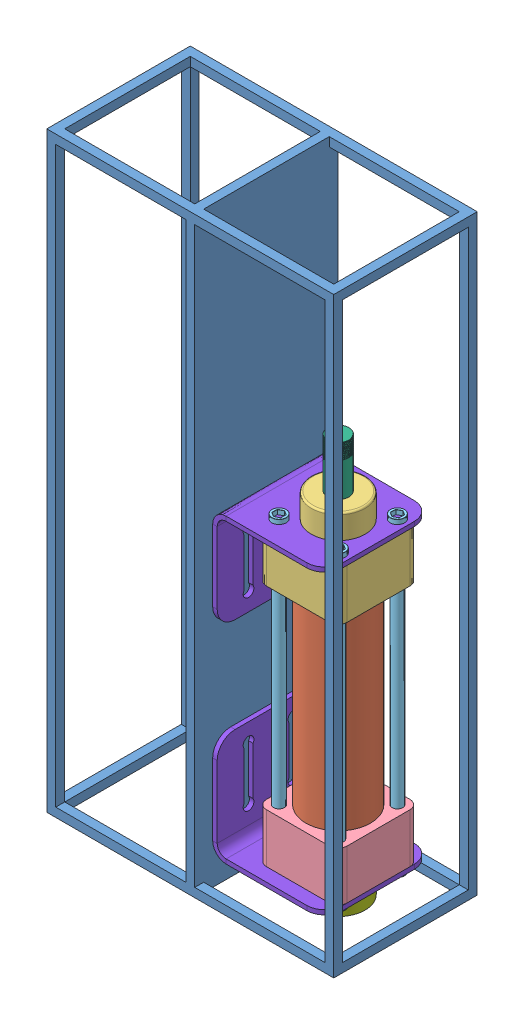
SolidWorks assembly Vertical Cylinder, configuration Default. Lengths in mm.
Overall size (160 330 80).
13 component instances, 8 part files, 3 mates.
Components (placement in the parent):
- Vertical Support-1: Vertical Support [Default] at (89.3378 424.6632 360.7176) x (1 0 0) z (0 -1 0) size (160 80 330)
- pnumetic cylinder-1: pnumetic cylinder [Default] at (92.3698 80.2595 293.179) x (-0.035384 0 0.999374) z (0 1 0) size (62.17 64.58 222.63) (flexible)
  - cylinder tube-1: cylinder tube [Default] at (103.244 123.1984 58.4037) size (36 36 110)
  - cylinder part one-1: cylinder part one [Default] at (126.5261 101.5086 194.9037) x (0.035384 -0.999374 0) z (0 0 -1) size (45 45 43.5)
  - cylinder part two1-1: cylinder part two1 [Default] at (124.9338 146.4804 31.9037) x (-0.035384 0.999374 0) z (0 0 1) size (45 45 27.5)
  - cylinder bolt-1: cylinder bolt [Default] at (87.3382 106.1249 113.4037) x (1 0 0) z (0 1 0) size (8 173 8)
  - cylinder bolt-2: cylinder bolt [Default] at (120.3176 107.2925 113.4037) x (1 0 0) z (0 1 0) size (8 173 8)
  - cylinder bolt-3: cylinder bolt [Default] at (119.1499 140.2719 113.4037) x (1 0 0) z (0 1 0) size (8 173 8)
  - cylinder bolt-4: cylinder bolt [Default] at (86.1705 139.1042 113.4037) x (1 0 0) z (0 1 0) size (8 173 8)
  - piston-1: piston [Default] at (103.244 123.1984 58.4037) x (0.106254 -0.994339 0) z (0 0 1) size (32 32 180.13)
  - extra part-1: extra part [Default] at (103.244 123.1984 15.9037) size (30 30 16)
  - fixation-2: fixation [Default] at (134.7291 81.7865 139.9037) x (-0.999374 -0.035384 0) z (-0.035384 0.999374 0) size (60 57.5 62.5)
  - fixation-3: fixation [Default] at (74.7667 79.6635 86.9037) x (0.999374 0.035384 0) z (-0.035384 0.999374 0) size (60 57.5 62.5)
Mates (geometry in assembly coordinates):
- Coincident1: coincident anti-aligned: plane of Vertical Support-1 through (171.8378 419.6632 360.7176) normal (1 0 0); plane of pnumetic cylinder-1/fixation-2 through (171.8378 220.1632 430.7176) normal (-1 0 0)
- Width1: width anti-aligned: plane of pnumetic cylinder-1/fixation-3 through (234.3378 112.1632 370.7176) normal (0 0 -1); plane of Vertical Support-1 through (234.3378 112.1632 430.7176) normal (0 0 1); plane of pnumetic cylinder-1/fixation-3 through (89.3378 419.6632 440.7176) normal (0 0 1); plane of Vertical Support-1 through (89.3378 419.6632 360.7176) normal (0 0 -1)
- Distance1: distance = 15 mm aligned: plane of pnumetic cylinder-1/fixation-3 through (234.3378 109.6632 370.7176) normal (0 -1 0); plane of Vertical Support-1 through (89.3378 94.6632 360.7176) normal (0 -1 0)
